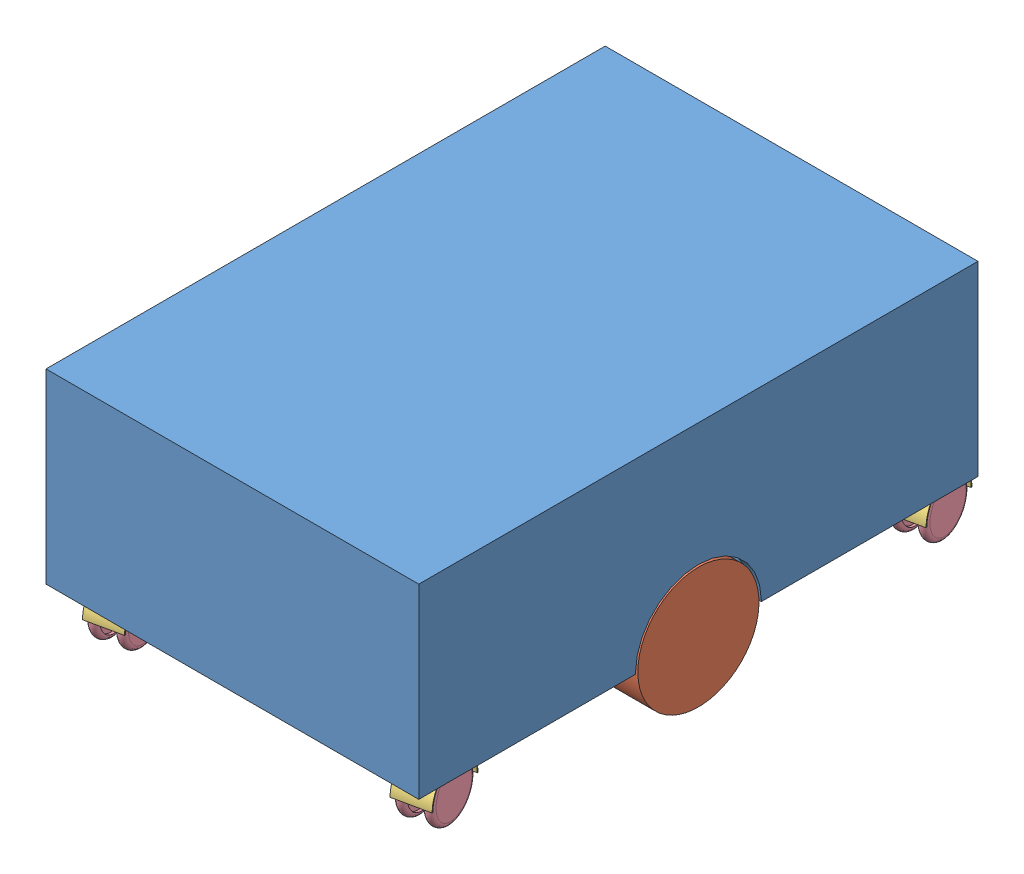
SolidWorks assembly Assem1, configuration Default. Lengths in mm.
Overall size (451 290.78 626.74).
15 component instances, 4 part files, 10 mates.
Components (placement in the parent):
- Frame-1: Frame [Default] at (-186.3224 -70.505 -327.2559) size (400 224.2 600)
- Wheel-1: Wheel [Default] at (-186.3224 -69.705 -27.2559) x (1 0 0) z (0 0.643492 -0.765453) size (80 130 130)
- Wheel-3: Wheel [Default] at (213.6776 -69.705 -27.2559) x (-1 0 0) z (0 -0.043931 -0.999035) size (80 130 130)
- caster joint-1: caster joint [Default] at (-155.7734 -104.505 -313.0346) x (0.977817 0 -0.209461) z (0.209461 0 0.977817) size (38 57.53 64)
- caster wheel2-1: caster wheel2 [Default] at (-154.7956 -104.505 -313.244) x (0.977817 0 -0.209461) z (0.010755 -0.998681 0.050208) size (17 60 60)
- caster wheel2-2: caster wheel2 [Default] at (-156.7513 -104.505 -312.8251) x (-0.977817 0 0.209461) z (-0.165152 0.615087 -0.770969) size (17 60 60)
- caster wheel2-3: caster wheel2 [Default] at (-154.7956 -104.505 216.756) x (0.977817 0 -0.209461) z (0.010755 -0.998681 0.050208) size (17 60 60)
- caster wheel2-4: caster wheel2 [Default] at (175.2044 -104.505 -313.244) x (0.977817 0 -0.209461) z (0.010755 -0.998681 0.050208) size (17 60 60)
- caster wheel2-5: caster wheel2 [Default] at (175.2044 -104.505 216.756) x (0.977817 0 -0.209461) z (0.010755 -0.998681 0.050208) size (17 60 60)
- caster wheel2-6: caster wheel2 [Default] at (-156.7513 -104.505 217.1749) x (-0.977817 0 0.209461) z (-0.165152 0.615087 -0.770969) size (17 60 60)
- caster wheel2-7: caster wheel2 [Default] at (173.2487 -104.505 -312.8251) x (-0.977817 0 0.209461) z (-0.165152 0.615087 -0.770969) size (17 60 60)
- caster wheel2-8: caster wheel2 [Default] at (173.2487 -104.505 217.1749) x (-0.977817 0 0.209461) z (-0.165152 0.615087 -0.770969) size (17 60 60)
- caster joint-2: caster joint [Default] at (-155.7734 -104.505 216.9654) x (0.977817 0 -0.209461) z (0.209461 0 0.977817) size (38 57.53 64)
- caster joint-3: caster joint [Default] at (174.2266 -104.505 -313.0346) x (0.977817 0 -0.209461) z (0.209461 0 0.977817) size (38 57.53 64)
- caster joint-4: caster joint [Default] at (174.2266 -104.505 216.9654) x (0.977817 0 -0.209461) z (0.209461 0 0.977817) size (38 57.53 64)
Mates (geometry in assembly coordinates):
- Concentric2: concentric aligned: circle of Wheel-1; circle of Frame-1
- Concentric3: concentric anti-aligned: circle of Wheel-3; circle of Frame-1
- Concentric4: concentric aligned: cylinder of Frame-1 through (-151.3224 -67.505 -292.2559) axis (0 1 0) radius 5; cylinder of caster joint-1 through (-151.3224 -90.505 -292.2559) axis (0 1 0) radius 7
- Coincident23: coincident aligned: circle of Frame-1; plane of caster joint-1 through (-151.3224 -52.505 -292.2559) normal (0 1 0)
- Concentric6: concentric anti-aligned: cylinder of caster joint-1 through (-154.7956 -104.505 -313.244) axis (0.977817 0 -0.209461) radius 5; cylinder of caster wheel2-1 through (-154.7956 -104.505 -313.244) axis (-0.977817 0 0.209461) radius 5
- Coincident24: coincident anti-aligned: circle of caster joint-1; plane of caster wheel2-1 through (-154.7956 -104.505 -313.244) normal (-0.977817 0 0.209461)
- Concentric7: concentric anti-aligned: cylinder of caster joint-1 through (-156.7513 -104.505 -312.8251) axis (-0.977817 0 0.209461) radius 5; cylinder of caster wheel2-2 through (-156.7513 -104.505 -312.8251) axis (0.977817 0 -0.209461) radius 5
- Coincident25: coincident aligned: circle of caster joint-1; plane of caster wheel2-2 through (-156.7513 -104.505 -312.8251) normal (0.977817 0 -0.209461)
- Coincident26: coincident aligned: circle of Frame-1; plane of Wheel-1 through (-106.3224 -69.705 -27.2559) normal (1 0 0)
- Coincident27: coincident anti-aligned: circle of Frame-1; plane of Wheel-3 through (133.6776 -69.705 -27.2559) normal (-1 0 0)
